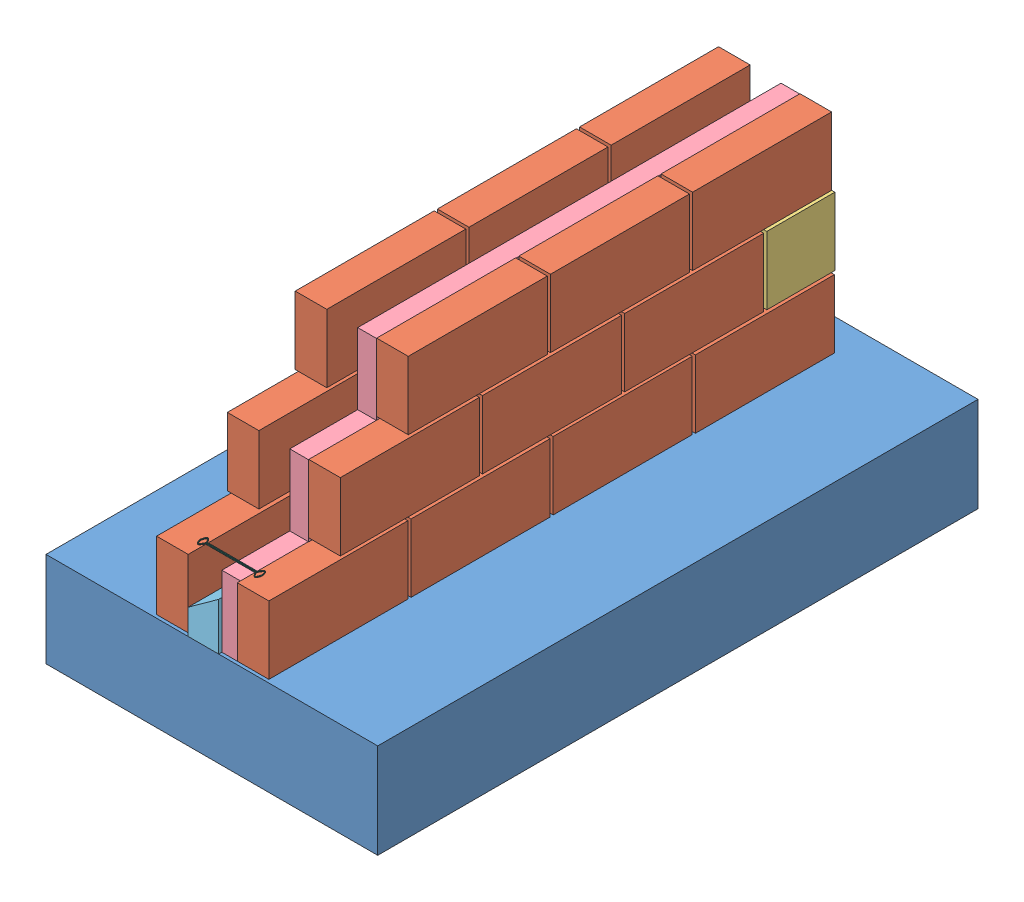
SolidWorks assembly Block Cavity Wall, configuration Default. Lengths in mm.
Overall size (1050 976.15 1900).
26 component instances, 6 part files, 35 mates.
Components (placement in the parent):
- Foundation 900 by 300-1: Foundation 900 by 300 [Default] at (-447.7084 -187.3596 -15.4042) size (1050 300 1900)
- Full Block-1: Full Block [Default] at (-97.7084 122.6404 494.5958) size (100 215 440)
- Full Block-2: Full Block [Default] at (-97.7084 122.4731 44.5972) size (100 215 440)
- Full Block-3: Full Block [Default] at (-97.7084 123.451 -405.3549) size (100 215 440)
- Full Block-4: Full Block [Default] at (-97.7084 122.228 -855.2798) size (100 215 440)
- Full Block-9: Full Block [Default] at (157.7084 122.6404 494.5958) size (100 215 440)
- Full Block-10: Full Block [Default] at (157.7084 122.4731 44.5972) size (100 215 440)
- Full Block-11: Full Block [Default] at (157.7084 123.451 -405.3549) size (100 215 440)
- Full Block-12: Full Block [Default] at (157.7084 122.228 -855.2798) size (100 215 440)
- Full Block-13: Full Block [Default] at (-98.893 348.7871 269.5925) size (100 215 440)
- Full Block-14: Full Block [Default] at (-98.893 348.7871 -180.4075) size (100 215 440)
- Full Block-15: Full Block [Default] at (-98.893 348.7871 -630.4075) size (100 215 440)
- Half Block-1: Half Block [Default] at (-98.893 348.7871 -855.4075) size (100 215 215)
- Full Block-16: Full Block [Default] at (158.893 348.7871 269.5925) size (100 215 440)
- Full Block-17: Full Block [Default] at (158.893 348.7871 -180.4075) size (100 215 440)
- Full Block-18: Full Block [Default] at (158.893 348.7871 -630.4075) size (100 215 440)
- Half Block-2: Half Block [Default] at (158.893 348.7871 -855.4075) size (100 215 215)
- Full Block-19: Full Block [Default] at (158.893 573.7871 54.5925) size (100 215 440)
- Full Block-20: Full Block [Default] at (158.893 573.7871 -395.4075) size (100 215 440)
- Full Block-21: Full Block [Default] at (158.893 573.7871 -845.4075) size (100 215 440)
- Full Block-22: Full Block [Default] at (-98.893 573.7871 54.5925) size (100 215 440)
- Full Block-23: Full Block [Default] at (-98.893 573.7871 -395.4075) size (100 215 440)
- Full Block-24: Full Block [Default] at (-98.893 573.7871 -845.4075) size (100 215 440)
- Cavity Insulation-1: Cavity Insulation [Default] at (128.893 447.8624 45.566) x (0 0 1) z (-1 0 0) size (1770 675 60)
- Concrete Fill-1: Concrete Fill [Default] at (4.5171 116.6984 -855.4042) size (97 150 1790)
- Cavity Tie-2: Cavity Tie [Default] at (80.9007 337.6404 876.5329) size (200.28 4.57 35.23)
Mates (geometry in assembly coordinates):
- Coincident1: coincident aligned: plane of Foundation 900 by 300-1 through (-447.7084 112.6404 934.5958) normal (0 0 1); plane of Full Block-1 through (-97.7084 337.6404 934.5958) normal (0 0 1)
- Distance1: distance = 10 mm: line of Full Block-1 through (-97.7084 122.6404 934.5958) axis (1 0 0); line of Foundation 900 by 300-1 through (602.2916 112.6404 934.5958) axis (-1 0 0)
- Distance2: distance = 350 mm: line of Foundation 900 by 300-1 through (-447.7084 112.6404 934.5958) axis (0 -1 0); line of Full Block-1 through (-97.7084 337.6404 934.5958) axis (0 -1 0)
- Coincident4: coincident aligned: plane of Full Block-1 through (-97.7084 122.6404 934.5958) normal (-1 0 0); plane of Full Block-2 through (-97.7084 122.4731 484.5972) normal (-1 0 0)
- Distance3: distance = 10 mm: line of Full Block-2 through (2.2916 337.4731 484.5972) axis (-1 0 0); line of Full Block-1 through (2.2916 337.6404 494.5958) axis (-1 0 0)
- Coincident7: coincident aligned: plane of Full Block-2 through (-97.7084 122.4731 484.5972) normal (-1 0 0); plane of Full Block-3 through (-97.7084 123.451 34.6451) normal (-1 0 0)
- Distance5: distance = 10 mm: line of Full Block-2 through (2.2916 337.4731 44.5972) axis (-1 0 0); line of Full Block-3 through (2.2916 338.451 34.6451) axis (-1 0 0)
- Coincident9: coincident aligned: plane of Full Block-3 through (-97.7084 123.451 34.6451) normal (-1 0 0); plane of Full Block-4 through (-97.7084 122.228 -415.2798) normal (-1 0 0)
- Distance6: distance = 10 mm: line of Full Block-4 through (2.2916 337.228 -415.2798) axis (-1 0 0); line of Full Block-3 through (2.2916 338.451 -405.3549) axis (-1 0 0)
- Distance8: distance = 215 mm: line of Full Block-13 through (-98.893 563.7871 709.5925) axis (0 -1 0); line of Full Block-1 through (-97.7084 337.6404 494.5958) axis (0 -1 0)
- Coincident18: coincident aligned: plane of Full Block-13; plane of Full Block-14 through (-98.893 348.7871 259.5925) normal (-1 0 0)
- Distance10: distance = 10 mm: line of Full Block-14 through (-98.893 563.7871 259.5925) axis (0 -1 0); line of Full Block-13 through (-98.893 563.7871 269.5925) axis (0 -1 0)
- Coincident23: coincident aligned: plane of Full Block-13 through (-98.893 563.7871 709.5925) normal (0 1 0); plane of Full Block-14 through (-98.893 563.7871 259.5925) normal (0 1 0)
- Coincident24: coincident aligned: plane of Full Block-14 through (-98.893 348.7871 259.5925) normal (-1 0 0); plane of Full Block-15 through (-98.893 348.7871 -190.4075) normal (-1 0 0)
- Distance14: distance = 10 mm: line of Full Block-14 through (1.107 563.7871 -180.4075) axis (-1 0 0); line of Full Block-15 through (1.107 563.7871 -190.4075) axis (-1 0 0)
- Coincident26: coincident aligned: plane of Full Block-14 through (-98.893 563.7871 259.5925) normal (0 1 0); plane of Full Block-15 through (-98.893 563.7871 -190.4075) normal (0 1 0)
- Coincident27: coincident aligned: plane of Full Block-15 through (-98.893 348.7871 -190.4075) normal (-1 0 0); plane of Half Block-1 through (-98.893 348.7871 -640.4075) normal (-1 0 0)
- Coincident28: coincident aligned: plane of Full Block-15 through (-98.893 563.7871 -190.4075) normal (0 1 0); plane of Half Block-1 through (-98.893 563.7871 -640.4075) normal (0 1 0)
- Distance15: distance = 10 mm: line of Full Block-15 through (-98.893 563.7871 -630.4075) axis (0 -1 0); line of Half Block-1 through (-98.893 563.7871 -640.4075) axis (0 -1 0)
- Coincident30: coincident aligned: plane of Full Block-16 through (158.893 348.7871 709.5925) normal (-1 0 0); plane of Full Block-19 through (158.893 573.7871 494.5925) normal (-1 0 0)
- Distance16: distance = 215 mm: line of Full Block-19 through (258.893 573.7871 54.5925) axis (0 1 0); line of Full Block-16 through (258.893 348.7871 269.5925) axis (0 1 0)
- Distance17: distance = 10 mm: line of Full Block-19 through (258.893 573.7871 494.5925) axis (0 0 -1); line of Full Block-16 through (258.893 563.7871 709.5925) axis (0 0 -1)
- Coincident33: coincident aligned: plane of Full Block-19 through (258.893 573.7871 494.5925) normal (1 0 0); plane of Full Block-20 through (258.893 573.7871 44.5925) normal (1 0 0)
- Coincident34: coincident aligned: plane of Full Block-19 through (158.893 788.7871 494.5925) normal (0 1 0); plane of Full Block-20 through (158.893 788.7871 44.5925) normal (0 1 0)
- Distance18: distance = 10 mm: line of Full Block-20 through (258.893 573.7871 44.5925) axis (0 1 0); line of Full Block-19 through (258.893 573.7871 54.5925) axis (0 1 0)
- Coincident36: coincident aligned: plane of Full Block-20 through (258.893 573.7871 44.5925) normal (1 0 0); plane of Full Block-21 through (258.893 573.7871 -405.4075) normal (1 0 0)
- Coincident37: coincident aligned: plane of Full Block-20 through (158.893 788.7871 44.5925) normal (0 1 0); plane of Full Block-21 through (158.893 788.7871 -405.4075) normal (0 1 0)
- Distance19: distance = 10 mm: line of Full Block-21 through (258.893 573.7871 -405.4075) axis (0 1 0); line of Full Block-20 through (258.893 573.7871 -395.4075) axis (0 1 0)
- Coincident39: coincident anti-aligned: plane of Full Block-19 through (158.893 573.7871 494.5925) normal (-1 0 0); plane of Cavity Insulation-1 through (158.893 787.6404 -845.4075) normal (1 0 0)
- Coincident41: coincident anti-aligned: plane of Foundation 900 by 300-1 through (-447.7084 112.6404 934.5958) normal (0 1 0); plane of Cavity Insulation-1 through (98.893 112.6404 924.5925) normal (0 -1 0)
- Coincident42: coincident aligned: plane of Full Block-21 through (158.893 788.7871 -845.4075) normal (0 0 -1); plane of Cavity Insulation-1 through (98.893 112.6404 -845.4075) normal (0 0 -1)
- Coincident43: coincident anti-aligned: plane of Foundation 900 by 300-1 through (-447.7084 112.6404 934.5958) normal (0 1 0); plane of Concrete Fill-1 through (98.893 112.6404 934.5958) normal (0 -1 0)
- Coincident44: coincident anti-aligned: line of Cavity Insulation-1 through (98.893 112.6404 -845.4075) axis (0 0 1); line of Concrete Fill-1 through (98.893 112.6404 934.5958) axis (0 0 -1)
- Coincident45: coincident aligned: plane of Full Block-9 through (157.7084 337.6404 934.5958) normal (0 0 1); plane of Concrete Fill-1 through (98.893 112.6404 934.5958) normal (0 0 1)
- Tangent1: tangent anti-aligned: plane of Full Block-9 through (157.7084 337.6404 934.5958) normal (0 1 0); cylinder of Cavity Tie-2 through (80.9007 338.3904 878.6003) axis (1 0 0) radius 0.75
